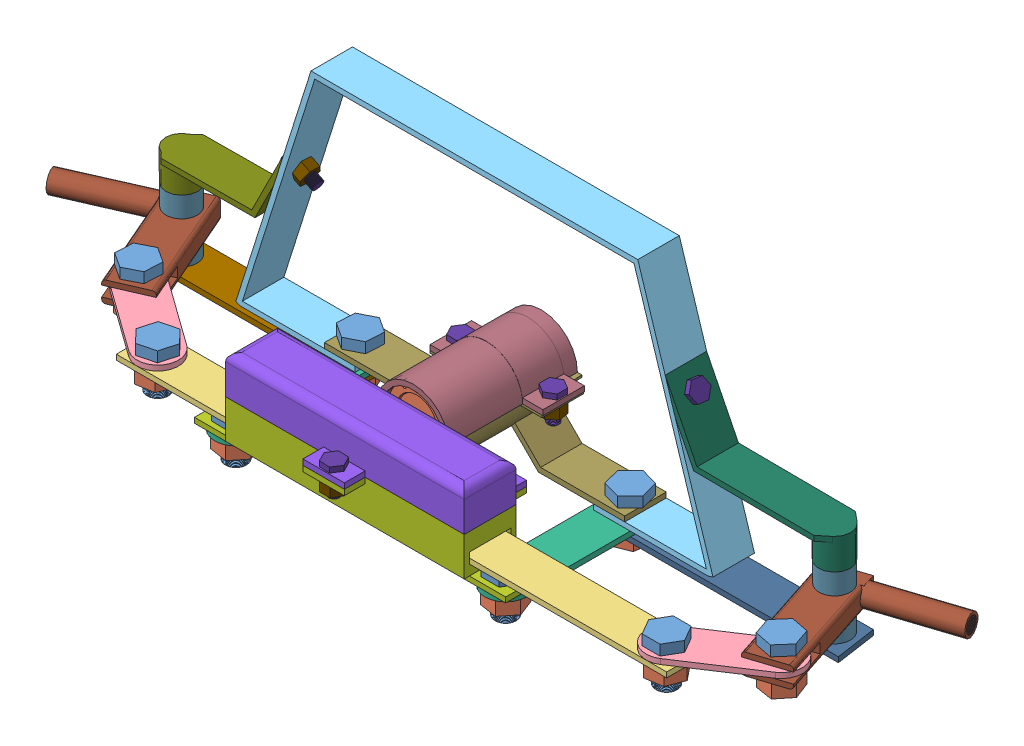
SolidWorks assembly Steering Mechanism, configuration Default. Lengths in mm.
Overall size (542.29 220.93 188.26).
52 component instances, 20 part files, 109 mates.
Components (placement in the parent):
- Pinon Gear-1: Pinon Gear [Default] at (18.0596 23.4154 -25.5289) x (0.999971 0.007586 0) z (0 0 1) size (28.79 28.79 12.7)
- 37d-gearmotor-100-131-150-encoder-1: 37d-gearmotor-100-131-150-encoder [Default] at (-1.8654 30.4154 -54.9751) size (36.8 36.8 90.1)
- Rack-1: Rack [Default] at (-58.7281 -0.9127 -25.3751) x (0.965926 -0.258819 0) z (0 0 1) size (326.19 90.25 25.4)
- Control Arm-1: Control Arm [Default] at (-149.1406 7.5404 -13.7125) x (-0.583389 0 0.812193) z (0 1 0) size (25.4 76.2 3.17)
- Control Arm-2: Control Arm [Default] at (205.3106 7.5404 -41.201) x (-0.549424 0 -0.835544) z (0 1 0) size (25.4 76.2 3.17)
- Front Wheel Bracket-1: Front Wheel Bracket [Default] at (7.9885 116.6287 -76.1751) x (1 0 0) z (0 0 -1) size (292.1 146.24 25.4)
- Short Rack Support Structure-1: Short Rack Support Structure [Default] at (83.7255 -5.1596 -55.7455) x (-1 0 0) z (0 -1 0) size (25.4 101.6 3.17)
- Short Rack Support Structure-2: Short Rack Support Structure [Default] at (-59.553 -5.1596 -45.8047) x (1 0 0) z (0 -1 0) size (25.4 101.6 3.17)
- Long Rack Support Structure-2: Long Rack Support Structure [Default] at (-38.0612 -5.1596 -14.7918) x (0 1 0) z (1 0 0) size (26.76 57.15 190.5)
- Long Rack Support Structure (Top)-1: Long Rack Support Structure (Top) [Default] at (37.6137 21.6016 3.1999) x (-1 0 0) z (0 0 -1) size (146.05 23.59 57.15)
- Pivot Arm (Left)-2: Pivot Arm (Left) [Default] at (-186.8809 -11.5096 -33.1605) x (-0.541489 0 0.840708) z (-0.840708 0 -0.541489) size (96.16 53.98 123.84)
- Pivot Arm (Right)-2: Pivot Arm (Right) [Default] at (211.0535 -8.3346 -33.1605) x (0.541489 0 0.840708) z (0.840708 0 -0.541489) size (104.82 53.97 137.29)
- Front Wheel Axles-3: Front Wheel Axles [Default] at (277.9295 11.2102 -114.4995) x (-0.310493 0 -0.950576) z (-0.950576 0 0.310493) size (76.2 13.19 76.21)
- Steering Motor Mount (Bottom)-2: Steering Motor Mount (Bottom) [Default] at (15.3381 12.3464 -101.5751) x (0 0 1) z (-1 0 0) size (78.58 31.27 183.81)
- Steering Motor Mount (Top)-2: Steering Motor Mount (Top) [Default] at (19.4781 29.2864 -76.1751) x (0 0 -1) z (1 0 0) size (78.58 22.18 69.09)
- Front Wheel Axles-4: Front Wheel Axles [Default] at (-240.1244 10.2206 -69.4744) x (-0.399781 0 -0.916611) z (0.916611 0 -0.399781) size (76.2 13.19 76.21)
- Spacer-1: Spacer [Default] at (229.822 -8.3346 -95.0926) x (0.991664 0 -0.128853) z (0.128853 0 0.991664) size (19.05 12.7 19.05)
- Spacer-2: Spacer [Default] at (-178.3747 -8.3346 -100.4751) x (0.523364 0 -0.852109) z (0.852109 0 0.523364) size (19.05 12.7 19.05)
- Spacer-3: Spacer [Default] at (-169.1502 17.0654 -93.7664) size (19.05 12.7 19.05)
- Spacer-4: Spacer [Default] at (230.5407 17.0654 -93.7664) size (19.05 12.7 19.05)
- Front Wheel Support-1: Front Wheel Support [Default] at (127.4023 52.8952 -76.1751) x (-0.999975 0.007006 0) z (0 0 -1) size (101.09 57.73 25.4)
- Front Wheel Support #2-1: Front Wheel Support #2 [Default] at (-103.2542 52.8183 -101.5751) x (0.999975 0.007006 0) z (0 0 1) size (85.09 57.73 25.4)
- 0.25in Hex Bolt-1: 0.25in Hex Bolt [Default] at (1.5398 307.5194 143.5864) x (-0.430629 -0.859999 0.273788) z (0.894165 -0.447737 0) size (11.2 12.9 19.05)
- 0.25in Hex Bolt-2: 0.25in Hex Bolt [Default] at (-17.0641 387.1538 -112.045) x (0.261641 -0.522518 -0.811491) z (-0.894165 -0.447737 0) size (11.2 12.9 19.05)
- 0.25in Nut-1: 0.25in Nut [Default] at (125.0268 72.0692 -88.8751) x (0.297793 -0.594716 -0.746748) z (0.894165 0.447737 0) size (12.9 11.18 6.49)
- 0.25in Nut-2: 0.25in Nut [Default] at (-101.1354 72.1209 -88.8751) x (0.403858 0.806536 0.431739) z (-0.894165 0.447737 0) size (12.9 11.18 6.49)
- 0.25in Hex Bolt-3: 0.25in Hex Bolt [Default] at (-118.1926 35.6364 214.9281) x (-0.491617 0 -0.870811) z (0 -1 0) size (11.2 12.9 19.05)
- 0.25in Hex Bolt-4: 0.25in Hex Bolt [Default] at (4.4078 28.1666 355.6025) x (-0.837169 0 -0.546944) z (0 -1 0) size (11.2 12.9 19.05)
- 0.25in Hex Bolt-5: 0.25in Hex Bolt [Default] at (-36.5422 28.1666 311.1525) x (-0.837169 0 -0.546944) z (0 -1 0) size (11.2 12.9 19.05)
- 0.25in Hex Bolt-6: 0.25in Hex Bolt [Default] at (-16.1952 35.6364 257.1775) x (-0.837169 0 -0.546944) z (0 -1 0) size (11.2 12.9 19.05)
- 0.25in Hex Bolt-7: 0.25in Hex Bolt [Default] at (52.3578 28.1666 311.1525) x (-0.837169 0 -0.546944) z (0 -1 0) size (11.2 12.9 19.05)
- 0.25in Nut-3: 0.25in Nut [Default] at (47.6747 21.5662 -88.8751) x (0.781177 0 -0.624309) z (0 1 0) size (12.9 11.18 6.49)
- 0.25in Nut-4: 0.25in Nut [Default] at (59.8346 11.8571 -34.9001) x (1 0 0) z (0 1 0) size (12.9 11.18 6.49)
- 0.25in Nut-5: 0.25in Nut [Default] at (11.8846 11.8554 9.5499) x (1 0 0) z (0 1 0) size (12.9 11.18 6.49)
- 0.25in Nut-6: 0.25in Nut [Default] at (-29.0654 11.8571 -34.9001) x (1 0 0) z (0 1 0) size (12.9 11.18 6.49)
- 0.25in Nut-7: 0.25in Nut [Default] at (-8.7184 21.5662 -88.8751) x (1 0 0) z (0 1 0) size (12.9 11.18 6.49)
- 0.5in Hex Bolt-1: 0.5in Hex Bolt [Default] at (235.7047 23.4154 -40.5859) x (0.98122 0 0.192894) z (0 -1 0) size (22 19.05 28.57)
- 0.5in Hex Bolt-2: 0.5in Hex Bolt [Default] at (193.2591 17.0654 -12.6751) x (1 0 0) z (0 -1 0) size (22 19.05 28.57)
- 0.5in Hex Bolt-3: 0.5in Hex Bolt [Default] at (-70.3463 7.5404 -88.8751) x (-0.837169 0 -0.546944) z (0 -1 0) size (22 19.05 28.57)
- 0.5in Hex Bolt-4: 0.5in Hex Bolt [Default] at (94.7596 4.3654 -12.6751) x (1 0 0) z (0 -1 0) size (22 19.05 28.57)
- 0.5in Hex Bolt-5: 0.5in Hex Bolt [Default] at (94.7596 7.5404 -88.8751) x (0.964084 0 0.265597) z (0 -1 0) size (22 19.05 28.57)
- 0.5in Hex Bolt-6: 0.5in Hex Bolt [Default] at (-70.3404 4.3654 -12.6751) x (0.999732 0 0.023139) z (0 -1 0) size (22 19.05 28.57)
- 0.5in Hex Bolt-7: 0.5in Hex Bolt [Default] at (-118.1909 17.0654 -12.6751) x (0.969144 0 -0.246494) z (0 -1 0) size (22 19.05 28.57)
- 0.5in Hex Bolt-8: 0.5in Hex Bolt [Default] at (-159.4503 23.4154 -42.3113) x (-0.837169 0 -0.546944) z (0 -1 0) size (22 19.05 28.57)
- 0.5in Nut-1: 0.5in Nut [Default] at (193.2591 4.3654 -12.6751) x (1 0 0) z (0 -1 0) size (21.73 20.53 9.68)
- 0.5in Nut-2: 0.5in Nut [Default] at (-159.4503 -5.1596 -42.3113) x (1 0 0) z (0 1 0) size (21.73 20.53 9.68)
- 0.5in Nut-3: 0.5in Nut [Default] at (-70.3404 -17.8596 -12.6751) x (1 0 0) z (0 1 0) size (21.73 20.53 9.68)
- 0.5in Nut-4: 0.5in Nut [Default] at (235.7047 -5.1596 -40.5859) x (1 0 0) z (0 1 0) size (21.73 20.53 9.68)
- 0.5in Nut-5: 0.5in Nut [Default] at (94.7596 -21.0346 -88.8751) x (-0.015272 0 -0.999883) z (0 1 0) size (21.73 20.53 9.68)
- 0.5in Nut-6: 0.5in Nut [Default] at (94.7596 -17.8596 -12.6751) x (1 0 0) z (0 1 0) size (21.73 20.53 9.68)
- 0.5in Nut-7: 0.5in Nut [Default] at (-118.1909 4.3654 -12.6751) x (1 0 0) z (0 -1 0) size (21.73 20.53 9.68)
- 0.5in Nut-8: 0.5in Nut [Default] at (-70.3463 -17.8596 -88.8751) x (1 0 0) z (0 1 0) size (21.73 20.53 9.68)
Mates (geometry in assembly coordinates):
- Parallel1: parallel aligned: plane of Pinon Gear-1 through (18.0596 23.4154 -12.8289) normal (0 0 1); plane of Rack-1 through (-58.7281 -0.9127 0.0249) normal (0 0 1)
- Parallel2: parallel aligned: line of 37d-gearmotor-100-131-150-encoder-1 through (16.2596 25.8154 -13.0501) axis (1 0 0); line of Rack-1 through (336.85 -130.8909 4.3654) axis (0.000025 1 0)
- Concentric6: concentric anti-aligned: circle of Pinon Gear-1; circle of 37d-gearmotor-100-131-150-encoder-1
- Concentric7: concentric anti-aligned: cylinder of Rack-1 through (-118.1909 -17.8596 -12.6751) axis (0 1 0) radius 6.35; cylinder of Control Arm-1 through (-118.1909 10.7154 -12.6751) axis (0 -1 0) radius 6.35
- Coincident9: coincident anti-aligned: plane of Rack-1 through (-58.7281 7.5404 0.0249) normal (0 1 0); plane of Control Arm-1 through (-149.1406 7.5404 -13.7125) normal (0 -1 0)
- Concentric11: concentric anti-aligned: cylinder of Front Wheel Bracket-1 through (94.7596 4.8404 -88.8751) axis (0 -1 0) radius 6.35; cylinder of Short Rack Support Structure-1 through (94.7596 -8.3346 -88.8751) axis (0 1 0) radius 6.35
- Coincident13: coincident anti-aligned: plane of Front Wheel Bracket-1 through (7.9885 -5.1596 -101.5751) normal (0 -1 0); plane of Short Rack Support Structure-1 through (83.7255 -5.1596 -55.7455) normal (0 1 0)
- Concentric12: concentric anti-aligned: circle of Front Wheel Bracket-1; cylinder of Short Rack Support Structure-2 through (-70.5871 -8.3346 -88.8751) axis (0 1 0) radius 6.35
- Coincident15: coincident anti-aligned: plane of Front Wheel Bracket-1 through (7.9885 -5.1596 -101.5751) normal (0 -1 0); plane of Short Rack Support Structure-2 through (-59.553 -5.1596 -45.8047) normal (0 1 0)
- Parallel5: parallel aligned: line of Front Wheel Bracket-1 through (158.1363 -4.2005 -101.5751) axis (0 0 1); line of Short Rack Support Structure-1 through (82.0596 -8.3346 -88.8751) axis (0 0 1)
- Coincident18: coincident anti-aligned: plane of Rack-1 through (-58.7281 4.3654 0.0249) normal (0 -1 0); plane of Long Rack Support Structure-2 through (-38.0612 4.3654 -14.7918) normal (0 1 0)
- Coincident19: coincident anti-aligned: line of Rack-1 through (-130.8909 4.3654 -25.3751) axis (1 0 0); line of Long Rack Support Structure-2 through (85.2346 4.3654 -25.3751) axis (-1 0 0)
- Concentric13: concentric aligned: cylinder of 37d-gearmotor-100-131-150-encoder-1 through (18.0596 23.4154 -13.0501) axis (0 0 -1) radius 3; cylinder of Long Rack Support Structure-2 through (18.0596 23.4154 -25.3751) axis (0 0 -1) radius 3.05
- Coincident20: coincident anti-aligned: plane of 37d-gearmotor-100-131-150-encoder-1 through (18.0596 30.4154 -28.5501) normal (0 0 1); plane of Long Rack Support Structure-2 through (-38.0612 45.6404 -28.5501) normal (0 0 -1)
- Coincident23: coincident anti-aligned: plane of Long Rack Support Structure-2 through (85.2346 21.6016 -79.3501) normal (0 1 0); plane of Long Rack Support Structure (Top)-1 through (85.2346 21.6016 -28.5501) normal (0 -1 0)
- Coincident25: coincident aligned: line of Long Rack Support Structure-2 through (-0.8154 21.6016 15.8999) axis (1 0 0); line of Long Rack Support Structure (Top)-1 through (-0.8154 21.6016 15.8999) axis (1 0 0)
- Coincident26: coincident: plane of Long Rack Support Structure-2 through (-60.8154 4.3654 0.0249) normal (-1 0 0); line of Long Rack Support Structure (Top)-1 through (-60.8154 21.6016 -28.5501) axis (0 0 1)
- Concentric26: concentric anti-aligned: cylinder of Rack-1 through (193.2591 -2.4596 -12.6751) axis (0 1 0) radius 6.35; cylinder of Control Arm-2 through (193.2591 10.7154 -12.6751) axis (0 -1 0) radius 6.35
- Parallel14: parallel anti-aligned: plane of Rack-1 through (-58.7281 7.5404 0.0249) normal (0 1 0); plane of Control Arm-2 through (205.3106 7.5404 -41.201) normal (0 -1 0)
- Concentric28: concentric anti-aligned: cylinder of Short Rack Support Structure-1 through (94.7596 -8.3346 -12.6751) axis (0 1 0) radius 6.35; cylinder of Long Rack Support Structure-2 through (94.7596 -1.9846 -12.6751) axis (0 -1 0) radius 6.35
- Coincident46: coincident anti-aligned: plane of Short Rack Support Structure-1 through (83.7255 -5.1596 -55.7455) normal (0 1 0); plane of Long Rack Support Structure-2 through (-38.0612 -5.1596 -14.7918) normal (0 -1 0)
- Parallel15: parallel aligned: line of Short Rack Support Structure-1 through (107.4596 -5.1596 -88.8751) axis (0 0 1); line of Long Rack Support Structure-2 through (107.4596 -1.9846 -25.3751) axis (0 0 1)
- Coincident48: coincident anti-aligned: plane of Rack-1 through (-58.7281 7.5404 0.0249) normal (0 1 0); plane of Control Arm-2 through (205.3106 7.5404 -41.201) normal (0 -1 0)
- Concentric29: concentric aligned: cylinder of Short Rack Support Structure-1 through (94.7596 -8.3346 -88.8751) axis (0 1 0) radius 6.35; cylinder of Pivot Arm (Right)-2 through (94.7596 -11.5096 -88.8751) axis (0 1 0) radius 5.0783
- Coincident49: coincident anti-aligned: plane of Short Rack Support Structure-1 through (83.7255 -8.3346 -55.7455) normal (0 -1 0); plane of Pivot Arm (Right)-2 through (211.0535 -8.3346 -33.1605) normal (0 1 0)
- Parallel16: parallel anti-aligned: line of Front Wheel Bracket-1 through (155.1096 -5.1596 -101.5751) axis (-1 0 0); line of Pivot Arm (Right)-2 through (80.0368 -11.5096 -101.5751) axis (1 0 0)
- Concentric30: concentric anti-aligned: cylinder of Short Rack Support Structure-2 through (-70.5871 -8.3346 -88.8751) axis (0 1 0) radius 6.35; cylinder of Pivot Arm (Left)-2 through (-70.5871 -8.3346 -88.8751) axis (0 -1 0) radius 5.0783
- Coincident51: coincident anti-aligned: plane of Short Rack Support Structure-2 through (-59.553 -8.3346 -45.8047) normal (0 -1 0); plane of Pivot Arm (Left)-2 through (-186.8809 -8.3346 -33.1605) normal (0 1 0)
- Parallel17: parallel aligned: line of Front Wheel Bracket-1 through (-60.9371 -5.1596 -101.5751) axis (-1 0 0); line of Pivot Arm (Left)-2 through (-55.8643 -8.3346 -101.5751) axis (-1 0 0)
- Concentric31: concentric anti-aligned: cylinder of Front Wheel Bracket-1 through (94.7596 4.8404 -88.8751) axis (0 -1 0) radius 6.35; cylinder of Steering Motor Mount (Bottom)-2 through (94.7596 -24.2096 -88.8751) axis (0 1 0) radius 6.35
- Coincident53: coincident anti-aligned: plane of Front Wheel Bracket-1 through (7.9885 -1.9846 -101.5751) normal (0 1 0); plane of Steering Motor Mount (Bottom)-2 through (15.3381 -1.9846 -76.1751) normal (0 -1 0)
- Coincident54: coincident aligned: plane of Front Wheel Bracket-1 through (7.9885 116.6287 -101.5751) normal (0 0 -1); plane of Steering Motor Mount (Bottom)-2 through (15.3381 12.3464 -101.5751) normal (0 0 -1)
- Coincident55: coincident aligned: circle of Steering Motor Mount (Bottom)-2; cylinder of Steering Motor Mount (Top)-2 through (-8.7184 7.0614 -88.8751) axis (0 1 0) radius 3.175
- Coincident57: coincident aligned: plane of Steering Motor Mount (Bottom)-2 through (15.3381 12.3464 -109.7501) normal (0 0 -1); plane of Steering Motor Mount (Top)-2 through (19.4781 29.2864 -109.7501) normal (0 0 -1)
- Coincident58: coincident anti-aligned: plane of Steering Motor Mount (Bottom)-2 through (15.3381 29.2864 -76.1751) normal (0 1 0); plane of Steering Motor Mount (Top)-2 through (19.4781 29.2864 -101.5751) normal (0 -1 0)
- Concentric32: concentric aligned: cylinder of Control Arm-2 through (235.7047 10.7154 -40.5859) axis (0 -1 0) radius 6.35; cylinder of Front Wheel Axles-3 through (235.7047 29.7654 -40.5859) axis (0 -1 0) radius 6.35
- Coincident59: coincident anti-aligned: plane of Control Arm-2 through (205.3106 7.5404 -41.201) normal (0 -1 0); plane of Front Wheel Axles-3 through (243.4417 7.5404 -56.4734) normal (0 1 0)
- Concentric33: concentric aligned: cylinder of Pivot Arm (Right)-2 through (219.9317 42.4654 -88.8751) axis (0 -1 0) radius 6.35; cylinder of Front Wheel Axles-3 through (219.9317 22.3654 -88.8751) axis (0 -1 0) radius 6.35
- Concentric34: concentric anti-aligned: cylinder of Control Arm-1 through (-159.4503 10.7154 -42.3113) axis (0 -1 0) radius 6.35; cylinder of Front Wheel Axles-4 through (-159.4503 -8.3346 -42.3113) axis (0 1 0) radius 6.35
- Coincident60: coincident anti-aligned: plane of Control Arm-1 through (-149.1406 7.5404 -13.7125) normal (0 -1 0); plane of Front Wheel Axles-4 through (-175.7903 7.5404 -49.0399) normal (0 1 0)
- Concentric35: concentric anti-aligned: cylinder of Pivot Arm (Left)-2 through (-179.7592 42.4654 -88.8751) axis (0 -1 0) radius 6.35; cylinder of Front Wheel Axles-4 through (-179.7592 -0.9346 -88.8751) axis (0 1 0) radius 6.35
- Concentric36: concentric aligned: cylinder of Pivot Arm (Right)-2 through (219.9317 42.4654 -88.8751) axis (0 -1 0) radius 6.35; cylinder of Spacer-1 through (219.9317 4.3654 -88.8751) axis (0 -1 0) radius 6.35
- Coincident61: coincident anti-aligned: plane of Pivot Arm (Right)-2 through (211.0535 -8.3346 -33.1605) normal (0 1 0); plane of Spacer-1 through (219.9317 -8.3346 -88.8751) normal (0 -1 0)
- Concentric37: concentric aligned: cylinder of Pivot Arm (Left)-2 through (-179.7592 42.4654 -88.8751) axis (0 -1 0) radius 6.35; cylinder of Spacer-2 through (-179.7592 4.3654 -88.8751) axis (0 -1 0) radius 6.35
- Coincident62: coincident anti-aligned: plane of Pivot Arm (Left)-2 through (-186.8809 -8.3346 -33.1605) normal (0 1 0); plane of Spacer-2 through (-179.7592 -8.3346 -88.8751) normal (0 -1 0)
- Coincident63: coincident anti-aligned: cylinder of Pivot Arm (Left)-2 through (-179.7592 42.4654 -88.8751) axis (0 -1 0) radius 6.35; circle of Spacer-3
- Coincident64: coincident anti-aligned: plane of Front Wheel Axles-4 through (-167.7401 17.0654 -94.1173) normal (0 1 0); plane of Spacer-3 through (-179.7592 17.0654 -88.8751) normal (0 -1 0)
- Concentric38: concentric aligned: cylinder of Pivot Arm (Right)-2 through (219.9317 42.4654 -88.8751) axis (0 -1 0) radius 6.35; cylinder of Spacer-4 through (219.9317 29.7654 -88.8751) axis (0 -1 0) radius 6.35
- Coincident65: coincident anti-aligned: plane of Front Wheel Axles-3 through (207.4673 17.0654 -84.8038) normal (0 1 0); plane of Spacer-4 through (219.9317 17.0654 -88.8751) normal (0 -1 0)
- Coincident66: coincident anti-aligned: plane of Front Wheel Bracket-1 through (112.0988 141.0796 -101.5751) normal (0.953282 0.302083 0); plane of Front Wheel Support-1 through (134.9789 68.8769 -101.5751) normal (-0.953282 -0.302083 0)
- Coincident68: coincident anti-aligned: line of Front Wheel Bracket-1 through (112.0988 141.0796 -76.1751) axis (0.302083 -0.953282 0); line of Front Wheel Support-1 through (134.9789 68.8769 -76.1751) axis (-0.302083 0.953282 0)
- Coincident72: coincident anti-aligned: plane of Front Wheel Bracket-1 through (-87.9262 141.0796 -101.5751) normal (-0.953282 0.302083 0); plane of Front Wheel Support #2-1 through (-110.8308 68.8 -76.1751) normal (0.953282 -0.302083 0)
- Coincident73: coincident aligned: line of Front Wheel Bracket-1 through (-133.9637 -4.2005 -101.5751) axis (0.302083 0.953282 0); line of Front Wheel Support #2-1 through (-110.8308 68.8 -101.5751) axis (0.302083 0.953282 0)
- Concentric44: concentric aligned: cylinder of Front Wheel Support #2-1 through (-107.5576 75.3367 -88.8751) axis (-0.894165 0.447737 0) radius 3.175; cylinder of 0.25in Hex Bolt-1 through (-96.2514 69.6754 -88.8751) axis (-0.894165 0.447737 0) radius 3.175
- Concentric45: concentric anti-aligned: cylinder of 0.25in Hex Bolt-1 through (-96.2514 69.6754 -88.8751) axis (-0.894165 0.447737 0) radius 3.175; cylinder of 0.25in Nut-2 through (-106.8133 74.964 -88.8751) axis (0.894165 -0.447737 0) radius 3.175
- Concentric46: concentric aligned: cylinder of Front Wheel Support-1 through (131.7058 75.4136 -88.8751) axis (0.894165 0.447737 0) radius 3.175; cylinder of 0.25in Hex Bolt-2 through (120.5311 69.8181 -88.8751) axis (0.894165 0.447737 0) radius 3.175
- Concentric47: concentric anti-aligned: cylinder of 0.25in Hex Bolt-2 through (120.5311 69.8181 -88.8751) axis (0.894165 0.447737 0) radius 3.175; cylinder of 0.25in Nut-1 through (130.7048 74.9124 -88.8751) axis (-0.894165 -0.447737 0) radius 3.175
- Concentric48: concentric aligned: cylinder of Steering Motor Mount (Top)-2 through (47.6747 7.0614 -88.8751) axis (0 1 0) radius 3.175; cylinder of 0.25in Hex Bolt-3 through (47.6747 16.5864 -88.8751) axis (0 1 0) radius 3.175
- Coincident78: coincident anti-aligned: plane of Steering Motor Mount (Top)-2 through (19.4781 32.4614 -101.5751) normal (0 1 0); plane of 0.25in Hex Bolt-3 through (-118.1926 32.4614 214.9281) normal (0 -1 0)
- Concentric49: concentric anti-aligned: cylinder of 0.25in Hex Bolt-3 through (47.6747 16.5864 -88.8751) axis (0 1 0) radius 3.175; cylinder of 0.25in Nut-3 through (47.6747 27.9162 -88.8751) axis (0 -1 0) radius 3.175
- Coincident79: coincident anti-aligned: plane of Steering Motor Mount (Bottom)-2 through (15.3381 27.9162 -76.1751) normal (0 -1 0); plane of 0.25in Nut-3 through (47.6747 27.9162 -88.8751) normal (0 1 0)
- Concentric50: concentric aligned: cylinder of Steering Motor Mount (Top)-2 through (-8.7184 7.0614 -88.8751) axis (0 1 0) radius 3.175; cylinder of 0.25in Hex Bolt-6 through (-8.7184 16.5864 -88.8751) axis (0 1 0) radius 3.175
- Coincident80: coincident anti-aligned: plane of Steering Motor Mount (Top)-2 through (19.4781 32.4614 -101.5751) normal (0 1 0); plane of 0.25in Hex Bolt-6 through (-16.1952 32.4614 257.1775) normal (0 -1 0)
- Concentric51: concentric anti-aligned: cylinder of 0.25in Hex Bolt-6 through (-8.7184 16.5864 -88.8751) axis (0 1 0) radius 3.175; cylinder of 0.25in Nut-7 through (-8.7184 27.9162 -88.8751) axis (0 -1 0) radius 3.175
- Coincident81: coincident anti-aligned: plane of Steering Motor Mount (Bottom)-2 through (15.3381 27.9162 -76.1751) normal (0 -1 0); plane of 0.25in Nut-7 through (-8.7184 27.9162 -88.8751) normal (0 1 0)
- Concentric52: concentric aligned: cylinder of Long Rack Support Structure (Top)-1 through (59.8346 12.2916 -34.9001) axis (0 1 0) radius 3.175; cylinder of 0.25in Hex Bolt-7 through (59.8346 9.1166 -34.9001) axis (0 1 0) radius 3.175
- Coincident82: coincident anti-aligned: plane of Long Rack Support Structure (Top)-1 through (78.8846 24.9916 -41.2501) normal (0 1 0); plane of 0.25in Hex Bolt-7 through (52.3578 24.9916 311.1525) normal (0 -1 0)
- Concentric53: concentric anti-aligned: cylinder of 0.25in Hex Bolt-7 through (59.8346 9.1166 -34.9001) axis (0 1 0) radius 3.175; cylinder of 0.25in Nut-4 through (59.8346 18.2071 -34.9001) axis (0 -1 0) radius 3.175
- Coincident83: coincident anti-aligned: plane of Long Rack Support Structure-2 through (78.8846 18.2071 -41.2501) normal (0 -1 0); plane of 0.25in Nut-4 through (59.8346 18.2071 -34.9001) normal (0 1 0)
- Concentric54: concentric aligned: cylinder of Long Rack Support Structure (Top)-1 through (-29.0654 12.2916 -34.9001) axis (0 1 0) radius 3.175; cylinder of 0.25in Hex Bolt-5 through (-29.0654 9.1166 -34.9001) axis (0 1 0) radius 3.175
- Coincident84: coincident anti-aligned: plane of Long Rack Support Structure (Top)-1 through (-3.6654 24.9916 -41.2501) normal (0 1 0); plane of 0.25in Hex Bolt-5 through (-36.5422 24.9916 311.1525) normal (0 -1 0)
- Concentric55: concentric anti-aligned: cylinder of 0.25in Hex Bolt-5 through (-29.0654 9.1166 -34.9001) axis (0 1 0) radius 3.175; cylinder of 0.25in Nut-6 through (-29.0654 18.2071 -34.9001) axis (0 -1 0) radius 3.175
- Coincident85: coincident anti-aligned: plane of Long Rack Support Structure-2 through (-3.6654 18.2071 -41.2501) normal (0 -1 0); plane of 0.25in Nut-6 through (-29.0654 18.2071 -34.9001) normal (0 1 0)
- Concentric56: concentric aligned: cylinder of Long Rack Support Structure (Top)-1 through (11.8846 12.2916 9.5499) axis (0 1 0) radius 3.175; cylinder of 0.25in Hex Bolt-4 through (11.8846 9.1166 9.5499) axis (0 1 0) radius 3.175
- Coincident86: coincident anti-aligned: plane of Long Rack Support Structure (Top)-1 through (-0.8154 24.9916 15.8999) normal (0 1 0); plane of 0.25in Hex Bolt-4 through (4.4078 24.9916 355.6025) normal (0 -1 0)
- Concentric57: concentric anti-aligned: cylinder of 0.25in Hex Bolt-4 through (11.8846 9.1166 9.5499) axis (0 1 0) radius 3.175; cylinder of 0.25in Nut-5 through (11.8846 18.2054 9.5499) axis (0 -1 0) radius 3.175
- Coincident88: coincident anti-aligned: plane of Long Rack Support Structure-2 through (-0.8154 18.2054 15.8999) normal (0 -1 0); plane of 0.25in Nut-5 through (11.8846 18.2054 9.5499) normal (0 1 0)
- Concentric58: concentric anti-aligned: cylinder of Front Wheel Axles-3 through (235.7047 29.7654 -40.5859) axis (0 -1 0) radius 6.35; cylinder of 0.5in Hex Bolt-1 through (235.7047 -5.1596 -40.5859) axis (0 1 0) radius 6.35
- Coincident89: coincident anti-aligned: plane of Front Wheel Axles-3 through (207.4673 17.0654 -84.8038) normal (0 1 0); plane of 0.5in Hex Bolt-1 through (235.7047 17.0654 -40.5859) normal (0 -1 0)
- Concentric59: concentric anti-aligned: cylinder of 0.5in Hex Bolt-1 through (235.7047 -5.1596 -40.5859) axis (0 1 0) radius 6.35; cylinder of 0.5in Nut-4 through (235.7047 4.3654 -40.5859) axis (0 -1 0) radius 6.35
- Coincident90: coincident anti-aligned: plane of Front Wheel Axles-3 through (207.4673 4.3654 -84.8038) normal (0 -1 0); plane of 0.5in Nut-4 through (235.7047 4.3654 -40.5859) normal (0 1 0)
- Concentric60: concentric anti-aligned: cylinder of Control Arm-2 through (193.2591 10.7154 -12.6751) axis (0 -1 0) radius 6.35; cylinder of 0.5in Hex Bolt-2 through (193.2591 -11.5096 -12.6751) axis (0 1 0) radius 6.35
- Coincident91: coincident anti-aligned: plane of Control Arm-2 through (205.3106 10.7154 -41.201) normal (0 1 0); plane of 0.5in Hex Bolt-2 through (193.2591 10.7154 -12.6751) normal (0 -1 0)
- Coincident92: coincident anti-aligned: cylinder of 0.5in Hex Bolt-2 through (193.2591 -11.5096 -12.6751) axis (0 1 0) radius 6.35; circle of 0.5in Nut-1
- Coincident93: coincident anti-aligned: plane of Rack-1 through (-58.7281 4.3654 0.0249) normal (0 -1 0); plane of 0.5in Nut-1 through (193.2591 4.3654 -12.6751) normal (0 1 0)
- Concentric61: concentric anti-aligned: cylinder of Long Rack Support Structure-2 through (94.7596 -1.9846 -12.6751) axis (0 -1 0) radius 6.35; cylinder of 0.5in Hex Bolt-4 through (94.7596 -24.2096 -12.6751) axis (0 1 0) radius 6.35
- Coincident94: coincident anti-aligned: plane of 0.5in Hex Bolt-4 through (94.7596 -1.9846 -12.6751) normal (0 -1 0); plane of Long Rack Support Structure-2 through (-38.0612 -1.9846 -14.7918) normal (0 1 0)
- Concentric62: concentric anti-aligned: cylinder of 0.5in Hex Bolt-4 through (94.7596 -24.2096 -12.6751) axis (0 1 0) radius 6.35; cylinder of 0.5in Nut-6 through (94.7596 -8.3346 -12.6751) axis (0 -1 0) radius 6.35
- Coincident95: coincident anti-aligned: plane of Short Rack Support Structure-1 through (83.7255 -8.3346 -55.7455) normal (0 -1 0); plane of 0.5in Nut-6 through (94.7596 -8.3346 -12.6751) normal (0 1 0)
- Concentric63: concentric aligned: cylinder of Steering Motor Mount (Bottom)-2 through (94.7596 -24.2096 -88.8751) axis (0 1 0) radius 6.35; cylinder of 0.5in Hex Bolt-5 through (94.7596 -21.0346 -88.8751) axis (0 1 0) radius 6.35
- Coincident96: coincident anti-aligned: plane of Steering Motor Mount (Bottom)-2 through (15.3381 1.1904 -76.1751) normal (0 1 0); plane of 0.5in Hex Bolt-5 through (94.7596 1.1904 -88.8751) normal (0 -1 0)
- Concentric64: concentric anti-aligned: cylinder of 0.5in Hex Bolt-5 through (94.7596 -21.0346 -88.8751) axis (0 1 0) radius 6.35; cylinder of 0.5in Nut-5 through (94.7596 -11.5096 -88.8751) axis (0 -1 0) radius 6.35
- Coincident97: coincident anti-aligned: plane of Pivot Arm (Right)-2 through (211.0535 -11.5096 -33.1605) normal (0 -1 0); plane of 0.5in Nut-5 through (94.7596 -11.5096 -88.8751) normal (0 1 0)
- Coincident98: coincident aligned: circle of Steering Motor Mount (Bottom)-2; cylinder of 0.5in Hex Bolt-3 through (-70.3463 -21.0346 -88.8751) axis (0 1 0) radius 6.35
- Coincident99: coincident: plane of Steering Motor Mount (Bottom)-2 through (15.3381 1.1904 -76.1751) normal (0 1 0); line of 0.5in Hex Bolt-3 through (-69.7405 1.1904 -99.8569) axis (0.837169 0 0.546944)
- Concentric65: concentric anti-aligned: cylinder of 0.5in Hex Bolt-3 through (-70.3463 -21.0346 -88.8751) axis (0 1 0) radius 6.35; cylinder of 0.5in Nut-8 through (-70.3463 -8.3346 -88.8751) axis (0 -1 0) radius 6.35
- Coincident100: coincident anti-aligned: plane of Short Rack Support Structure-2 through (-59.553 -8.3346 -45.8047) normal (0 -1 0); plane of 0.5in Nut-8 through (-70.3463 -8.3346 -88.8751) normal (0 1 0)
- Concentric67: concentric aligned: cylinder of Front Wheel Axles-4 through (-159.4503 -8.3346 -42.3113) axis (0 1 0) radius 6.35; cylinder of 0.5in Hex Bolt-8 through (-159.4503 -5.1596 -42.3113) axis (0 1 0) radius 6.35
- Coincident101: coincident: plane of Front Wheel Axles-4 through (-167.7401 17.0654 -94.1173) normal (0 1 0); line of 0.5in Hex Bolt-8 through (-160.0561 17.0654 -31.3295) axis (-0.837169 0 -0.546944)
- Concentric68: concentric anti-aligned: cylinder of 0.5in Hex Bolt-8 through (-159.4503 -5.1596 -42.3113) axis (0 1 0) radius 6.35; cylinder of 0.5in Nut-2 through (-159.4503 4.3654 -42.3113) axis (0 -1 0) radius 6.35
- Coincident102: coincident anti-aligned: plane of Front Wheel Axles-4 through (-167.7401 4.3654 -94.1173) normal (0 -1 0); plane of 0.5in Nut-2 through (-159.4503 4.3654 -42.3113) normal (0 1 0)
- Concentric69: concentric aligned: cylinder of 0.5in Hex Bolt-7 through (-118.1909 -11.5096 -12.6751) axis (0 1 0) radius 6.35; cylinder of 0.5in Nut-7 through (-118.1909 -5.1596 -12.6751) axis (0 1 0) radius 6.35
- Concentric70: concentric anti-aligned: cylinder of Control Arm-1 through (-118.1909 10.7154 -12.6751) axis (0 -1 0) radius 6.35; cylinder of 0.5in Hex Bolt-7 through (-118.1909 -11.5096 -12.6751) axis (0 1 0) radius 6.35
- Coincident103: coincident anti-aligned: plane of Control Arm-1 through (-149.1406 10.7154 -13.7125) normal (0 1 0); plane of 0.5in Hex Bolt-7 through (-118.1909 10.7154 -12.6751) normal (0 -1 0)
- Coincident104: coincident anti-aligned: plane of Rack-1 through (-58.7281 4.3654 0.0249) normal (0 -1 0); plane of 0.5in Nut-7 through (-118.1909 4.3654 -12.6751) normal (0 1 0)
- Concentric71: concentric anti-aligned: cylinder of Long Rack Support Structure-2 through (-70.3404 -1.9846 -12.6751) axis (0 -1 0) radius 6.35; cylinder of 0.5in Hex Bolt-6 through (-70.3404 -24.2096 -12.6751) axis (0 1 0) radius 6.35
- Coincident105: coincident anti-aligned: plane of Long Rack Support Structure-2 through (-38.0612 -1.9846 -14.7918) normal (0 1 0); plane of 0.5in Hex Bolt-6 through (-70.3404 -1.9846 -12.6751) normal (0 -1 0)
- Concentric72: concentric anti-aligned: cylinder of 0.5in Hex Bolt-6 through (-70.3404 -24.2096 -12.6751) axis (0 1 0) radius 6.35; cylinder of 0.5in Nut-3 through (-70.3404 -8.3346 -12.6751) axis (0 -1 0) radius 6.35
- Coincident106: coincident anti-aligned: plane of Short Rack Support Structure-2 through (-59.553 -8.3346 -45.8047) normal (0 -1 0); plane of 0.5in Nut-3 through (-70.3404 -8.3346 -12.6751) normal (0 1 0)
